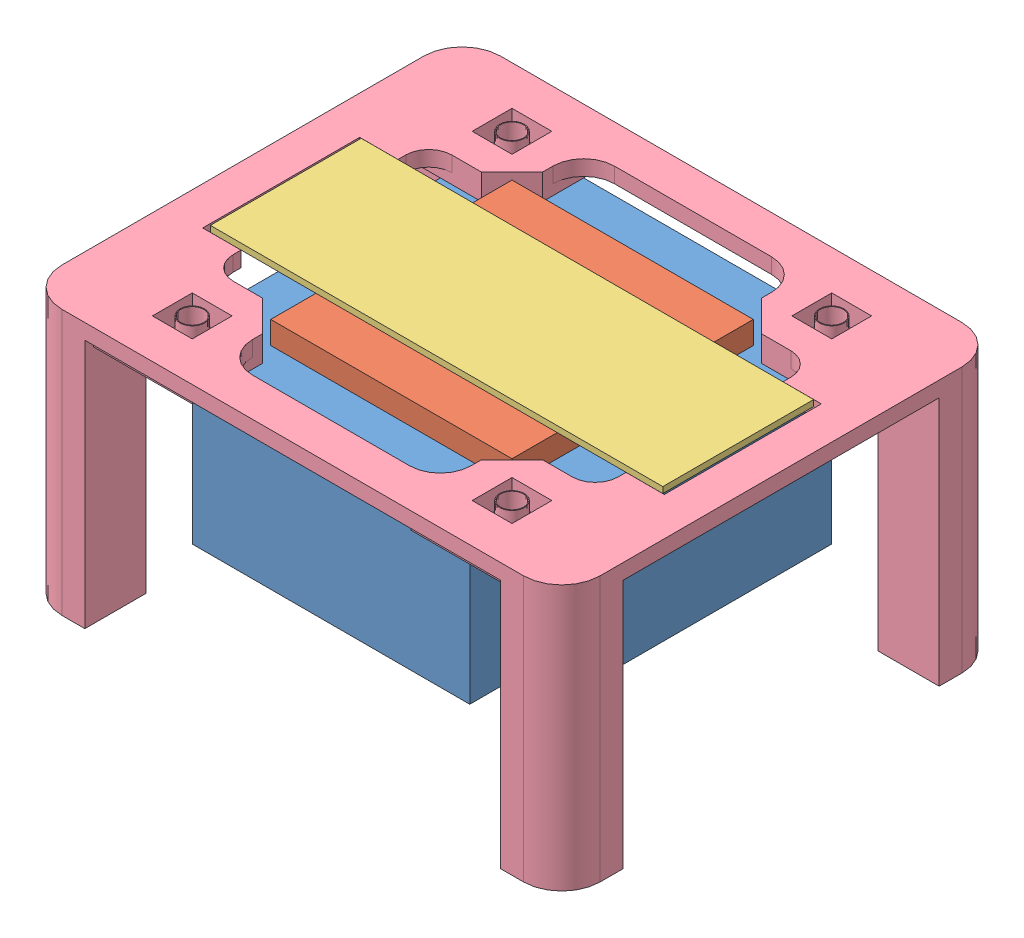
SolidWorks assembly Peltier_Slide_Stand, configuration Default. Lengths in mm.
Overall size (89.22 44.45 72.7).
6 component instances, 4 part files, 4 mates.
Components (placement in the parent):
- Slide_Peltier_Heatsink-1: Slide_Peltier_Heatsink [Default] at origin size (75 29.75 60)
  - HeatSink_Peltier-3: HeatSink_Peltier [Default] at (-10.0188 -2.8403 8.4903) size (60 28.75 60)
    - HeatSink-1: HeatSink [Default] at (-6.3433 -22.0506 -73.1894) x (1 0 0) z (0 0 -1) size (60 25 60)
    - Peltier_40mm-1: Peltier_40mm [Default] at (3.6567 -18.3006 -63.1894) x (1 0 0) z (0 -1 0) size (40 40 3.75)
  - Microscope_Slide-1: Microscope_Slide [Default] at (-23.8621 -21.1409 -22.1991) size (75 1 25)
- Part1^Peltier_Slide_Stand-1: Part1^Peltier_Slide_Stand [Default] at (0 -20.6409 0) x (1 0 0) z (0 1 0) size (89.22 72.7 43.95) (virtual)
Mates (geometry in assembly coordinates):
- InPlace1: in place: plane of ? through (0 60.3328 0) normal (0 1 0); moOrthogonalPlaneRef_w of ? through (0 60.3328 0) normal (0 0 -1); line of ? through (-55 0 60.3328) axis (0 1 0); unknown of Part1^Peltier_Slide_Stand-1
- Coincident1: coincident aligned: plane of Part1^Peltier_Slide_Stand-1; plane of assembly
- Coincident2: coincident aligned: plane of Part1^Peltier_Slide_Stand-1 through (0 -20.6409 0) normal (0 0 -1); moOrthogonalPlaneRef_w of assembly
- Coincident3: coincident anti-aligned: plane of Part1^Peltier_Slide_Stand-1; moOrthogonalPlaneRef_w of assembly
